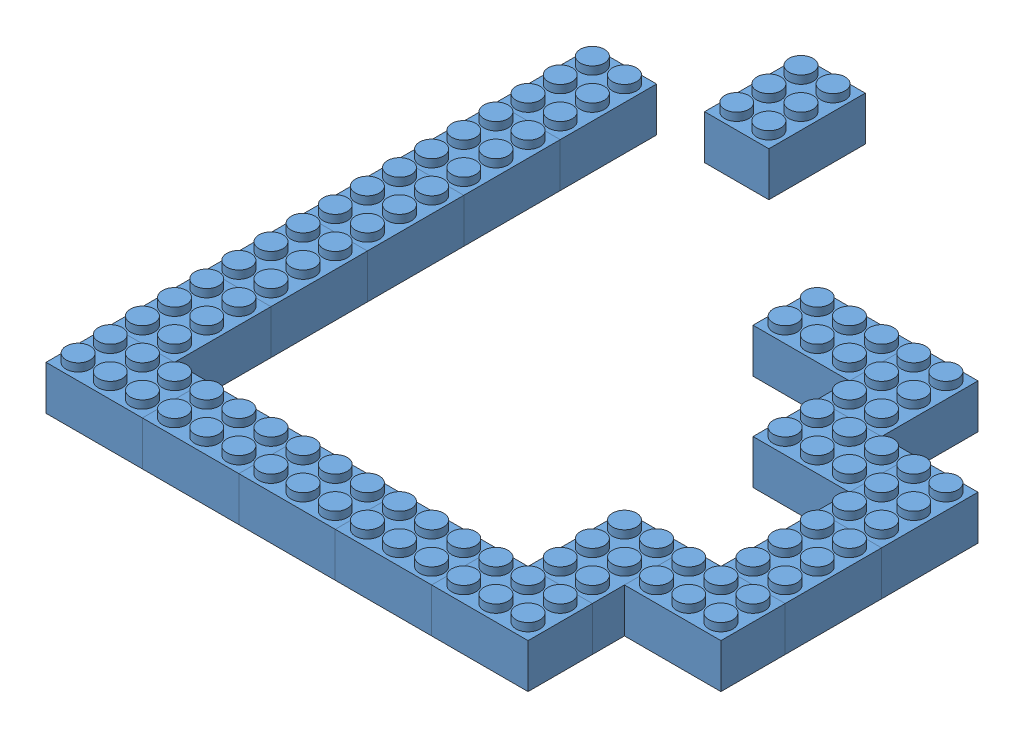
SolidWorks assembly Assem1, configuration Default. Lengths in mm.
Overall size (144 13 160).
18 component instances, 1 part files, 50 mates.
Components (placement in the parent):
- bokje maat 6-1: bokje maat 6 [Default] at (12.0166 -0.332 21.1269) size (24 13 16)
- bokje maat 6-2: bokje maat 6 [Default] at (-11.9834 -0.332 21.1269) size (24 13 16)
- bokje maat 6-3: bokje maat 6 [Default] at (36.0166 -0.332 21.1269) size (24 13 16)
- bokje maat 6-4: bokje maat 6 [Default] at (60.0166 -0.332 21.1269) size (24 13 16)
- bokje maat 6-5: bokje maat 6 [Default] at (64.0166 -0.332 1.1269) x (0 0 1) z (-1 0 0) size (24 13 16)
- bokje maat 6-6: bokje maat 6 [Default] at (84.0166 -0.332 -2.8731) size (24 13 16)
- bokje maat 6-7: bokje maat 6 [Default] at (88.0166 -0.332 -22.8731) x (0 0 -1) z (1 0 0) size (24 13 16)
- bokje maat 6-8: bokje maat 6 [Default] at (88.0166 -0.332 -46.8731) x (0 0 -1) z (1 0 0) size (24 13 16)
- bokje maat 6-9: bokje maat 6 [Default] at (68.0166 -0.332 -50.8731) size (24 13 16)
- bokje maat 6-10: bokje maat 6 [Default] at (64.0166 -0.332 -70.8731) x (0 0 -1) z (1 0 0) size (24 13 16)
- bokje maat 6-12: bokje maat 6 [Default] at (44.0166 -0.332 -74.8731) size (24 13 16)
- bokje maat 6-14: bokje maat 6 [Default] at (-35.9834 -0.332 21.1269) size (24 13 16)
- bokje maat 6-15: bokje maat 6 [Default] at (-39.9834 -0.332 1.1269) x (0 0 1) z (-1 0 0) size (24 13 16)
- bokje maat 6-16: bokje maat 6 [Default] at (-39.9834 -0.332 -22.8731) x (0 0 1) z (-1 0 0) size (24 13 16)
- bokje maat 6-17: bokje maat 6 [Default] at (-39.9834 -0.332 -46.8731) x (0 0 1) z (-1 0 0) size (24 13 16)
- bokje maat 6-18: bokje maat 6 [Default] at (-39.9834 -0.332 -70.8731) x (0 0 1) z (-1 0 0) size (24 13 16)
- bokje maat 6-19: bokje maat 6 [Default] at (-39.9834 -0.332 -94.8731) x (0 0 1) z (-1 0 0) size (24 13 16)
- bokje maat 6-20: bokje maat 6 [Default] at (-12.0471 -0.332 -118.8731) x (0 0 1) z (-1 0 0) size (24 13 16)
Mates (geometry in assembly coordinates):
- Coincident1: coincident anti-aligned: plane of bokje maat 6-1 through (0.0166 10.668 29.1269) normal (-1 0 0); plane of bokje maat 6-2 through (0.0166 10.668 29.1269) normal (1 0 0)
- Coincident2: coincident aligned: plane of bokje maat 6-1 through (12.0166 10.668 21.1269) normal (0 1 0); plane of bokje maat 6-2 through (-11.9834 10.668 21.1269) normal (0 1 0)
- Coincident3: coincident aligned: plane of bokje maat 6-1 through (24.0166 10.668 29.1269) normal (0 0 1); plane of bokje maat 6-2 through (0.0166 10.668 29.1269) normal (0 0 1)
- Coincident4: coincident anti-aligned: plane of bokje maat 6-1 through (24.0166 10.668 29.1269) normal (1 0 0); plane of bokje maat 6-3 through (24.0166 10.668 29.1269) normal (-1 0 0)
- Coincident5: coincident aligned: plane of bokje maat 6-1 through (24.0166 10.668 29.1269) normal (0 0 1); plane of bokje maat 6-3 through (48.0166 10.668 29.1269) normal (0 0 1)
- Coincident6: coincident aligned: plane of bokje maat 6-1 through (12.0166 10.668 21.1269) normal (0 1 0); plane of bokje maat 6-3 through (36.0166 10.668 21.1269) normal (0 1 0)
- Coincident7: coincident anti-aligned: plane of bokje maat 6-3 through (48.0166 10.668 29.1269) normal (1 0 0); plane of bokje maat 6-4 through (48.0166 10.668 29.1269) normal (-1 0 0)
- Coincident8: coincident aligned: plane of bokje maat 6-3 through (48.0166 10.668 29.1269) normal (0 0 1); plane of bokje maat 6-4 through (72.0166 10.668 29.1269) normal (0 0 1)
- Coincident9: coincident aligned: plane of bokje maat 6-3 through (36.0166 10.668 21.1269) normal (0 1 0); plane of bokje maat 6-4 through (60.0166 10.668 21.1269) normal (0 1 0)
- Coincident10: coincident anti-aligned: plane of bokje maat 6-4 through (72.0166 10.668 13.1269) normal (0 0 -1); plane of bokje maat 6-5 through (56.0166 10.668 13.1269) normal (0 0 1)
- Coincident11: coincident aligned: plane of bokje maat 6-4 through (72.0166 10.668 29.1269) normal (1 0 0); plane of bokje maat 6-5 through (72.0166 10.668 13.1269) normal (1 0 0)
- Coincident12: coincident aligned: plane of bokje maat 6-4 through (60.0166 10.668 21.1269) normal (0 1 0); plane of bokje maat 6-5 through (64.0166 10.668 1.1269) normal (0 1 0)
- Coincident13: coincident anti-aligned: plane of bokje maat 6-5 through (72.0166 10.668 13.1269) normal (1 0 0); plane of bokje maat 6-6 through (72.0166 10.668 5.1269) normal (-1 0 0)
- Coincident14: coincident aligned: plane of bokje maat 6-5 through (64.0166 10.668 1.1269) normal (0 1 0); plane of bokje maat 6-6 through (84.0166 10.668 -2.8731) normal (0 1 0)
- Coincident15: coincident aligned: plane of bokje maat 6-5 through (56.0166 10.668 -10.8731) normal (0 0 -1); plane of bokje maat 6-6 through (96.0166 10.668 -10.8731) normal (0 0 -1)
- Coincident16: coincident anti-aligned: plane of bokje maat 6-6 through (96.0166 10.668 -10.8731) normal (0 0 -1); plane of bokje maat 6-7 through (96.0166 10.668 -10.8731) normal (0 0 1)
- Coincident17: coincident aligned: plane of bokje maat 6-6 through (84.0166 10.668 -2.8731) normal (0 1 0); plane of bokje maat 6-7 through (88.0166 10.668 -22.8731) normal (0 1 0)
- Coincident18: coincident aligned: plane of bokje maat 6-6 through (96.0166 10.668 5.1269) normal (1 0 0); plane of bokje maat 6-7 through (96.0166 10.668 -34.8731) normal (1 0 0)
- Coincident19: coincident anti-aligned: plane of bokje maat 6-7 through (96.0166 10.668 -34.8731) normal (0 0 -1); plane of bokje maat 6-8 through (96.0166 10.668 -34.8731) normal (0 0 1)
- Coincident20: coincident aligned: plane of bokje maat 6-7 through (88.0166 10.668 -22.8731) normal (0 1 0); plane of bokje maat 6-8 through (88.0166 10.668 -46.8731) normal (0 1 0)
- Coincident21: coincident aligned: plane of bokje maat 6-7 through (96.0166 10.668 -34.8731) normal (1 0 0); plane of bokje maat 6-8 through (96.0166 10.668 -58.8731) normal (1 0 0)
- Coincident22: coincident anti-aligned: plane of bokje maat 6-8 through (80.0166 10.668 -58.8731) normal (-1 0 0); plane of bokje maat 6-9 through (80.0166 10.668 -42.8731) normal (1 0 0)
- Coincident23: coincident aligned: plane of bokje maat 6-8 through (96.0166 10.668 -58.8731) normal (0 0 -1); plane of bokje maat 6-9 through (80.0166 10.668 -58.8731) normal (0 0 -1)
- Coincident24: coincident aligned: plane of bokje maat 6-8 through (88.0166 10.668 -46.8731) normal (0 1 0); plane of bokje maat 6-9 through (68.0166 10.668 -50.8731) normal (0 1 0)
- Coincident25: coincident anti-aligned: plane of bokje maat 6-9 through (80.0166 10.668 -58.8731) normal (0 0 -1); plane of bokje maat 6-10 through (72.0166 10.668 -58.8731) normal (0 0 1)
- Coincident26: coincident aligned: plane of bokje maat 6-9 through (68.0166 10.668 -50.8731) normal (0 1 0); plane of bokje maat 6-10 through (64.0166 10.668 -70.8731) normal (0 1 0)
- Coincident27: coincident aligned: plane of bokje maat 6-9 through (56.0166 10.668 -42.8731) normal (-1 0 0); plane of bokje maat 6-10 through (56.0166 10.668 -82.8731) normal (-1 0 0)
- Coincident30: coincident anti-aligned: plane of bokje maat 6-10 through (56.0166 10.668 -82.8731) normal (-1 0 0); plane of bokje maat 6-12 through (56.0166 10.668 -66.8731) normal (1 0 0)
- Coincident31: coincident aligned: plane of bokje maat 6-10 through (64.0166 10.668 -70.8731) normal (0 1 0); plane of bokje maat 6-12 through (44.0166 10.668 -74.8731) normal (0 1 0)
- Coincident32: coincident aligned: plane of bokje maat 6-10 through (72.0166 10.668 -82.8731) normal (0 0 -1); plane of bokje maat 6-12 through (56.0166 10.668 -82.8731) normal (0 0 -1)
- Coincident34: coincident: plane of bokje maat 6-2 through (-23.9834 10.668 29.1269) normal (-1 0 0); plane of bokje maat 6-14 through (-23.9834 -0.7782 29.1269) normal (1 0 0)
- Coincident35: coincident: plane of bokje maat 6-2 through (0.0166 10.668 29.1269) normal (0 0 1); plane of bokje maat 6-14 through (-23.9834 -0.7782 29.1269) normal (0 0 1)
- Coincident36: coincident aligned: plane of bokje maat 6-2 through (-11.9834 10.668 21.1269) normal (0 1 0); plane of bokje maat 6-14 through (-35.9834 10.668 21.1269) normal (0 1 0)
- Coincident37: coincident: plane of bokje maat 6-14 through (-23.9834 10.668 13.1269) normal (0 0 -1); plane of bokje maat 6-15 through (-47.9834 4.2126 13.1269) normal (0 0 1)
- Coincident38: coincident: plane of bokje maat 6-14 through (-47.9834 10.668 29.1269) normal (-1 0 0); plane of bokje maat 6-15 through (-47.9834 4.2126 13.1269) normal (-1 0 0)
- Coincident39: coincident aligned: plane of bokje maat 6-14 through (-35.9834 10.668 21.1269) normal (0 1 0); plane of bokje maat 6-15 through (-39.9834 10.668 1.1269) normal (0 1 0)
- Coincident40: coincident: plane of bokje maat 6-15 through (-47.9834 10.668 -10.8731) normal (0 0 -1); plane of bokje maat 6-16 through (-49.3306 10.668 -10.8731) normal (0 0 1)
- Coincident41: coincident: plane of bokje maat 6-15 through (-39.9834 10.668 1.1269) normal (0 1 0); plane of bokje maat 6-16 through (-41.3306 10.668 -22.8731) normal (0 1 0)
- Coincident42: coincident aligned: plane of bokje maat 6-15 through (-47.9834 10.668 13.1269) normal (-1 0 0); plane of bokje maat 6-16 through (-47.9834 10.668 -10.8731) normal (-1 0 0)
- Coincident43: coincident: plane of bokje maat 6-16 through (-47.9834 10.668 -34.8731) normal (0 0 -1); plane of bokje maat 6-17 through (-47.9834 -0.2518 -34.8731) normal (0 0 1)
- Coincident44: coincident: plane of bokje maat 6-16 through (-47.9834 10.668 -10.8731) normal (-1 0 0); plane of bokje maat 6-17 through (-47.9834 -0.2518 -34.8731) normal (-1 0 0)
- Coincident45: coincident aligned: plane of bokje maat 6-16 through (-39.9834 10.668 -22.8731) normal (0 1 0); plane of bokje maat 6-17 through (-39.9834 10.668 -46.8731) normal (0 1 0)
- Coincident46: coincident: plane of bokje maat 6-17 through (-47.9834 10.668 -58.8731) normal (0 0 -1); plane of bokje maat 6-18 through (-47.9834 7.1699 -58.8731) normal (0 0 1)
- Coincident47: coincident: plane of bokje maat 6-17 through (-47.9834 10.668 -34.8731) normal (-1 0 0); plane of bokje maat 6-18 through (-47.9834 7.1699 -58.8731) normal (-1 0 0)
- Coincident48: coincident aligned: plane of bokje maat 6-17 through (-39.9834 10.668 -46.8731) normal (0 1 0); plane of bokje maat 6-18 through (-39.9834 10.668 -70.8731) normal (0 1 0)
- Coincident49: coincident: plane of bokje maat 6-18 through (-47.9834 10.668 -82.8731) normal (0 0 -1); plane of bokje maat 6-19 through (-37.7962 10.668 -82.8731) normal (0 0 1)
- Coincident50: coincident: plane of bokje maat 6-18 through (-39.9834 10.668 -70.8731) normal (0 1 0); plane of bokje maat 6-19 through (-29.7962 10.668 -94.8731) normal (0 1 0)
- Coincident51: coincident aligned: plane of bokje maat 6-18 through (-47.9834 10.668 -58.8731) normal (-1 0 0); plane of bokje maat 6-19 through (-47.9834 10.668 -82.8731) normal (-1 0 0)
- Coincident52: coincident: plane of bokje maat 6-19 through (-47.9834 10.668 -106.8731) normal (0 0 -1); plane of bokje maat 6-20 through (-20.0471 14.9504 -106.8731) normal (0 0 1)
- Coincident53: coincident aligned: plane of bokje maat 6-19 through (-39.9834 10.668 -94.8731) normal (0 1 0); plane of bokje maat 6-20 through (-12.0471 10.668 -118.8731) normal (0 1 0)
